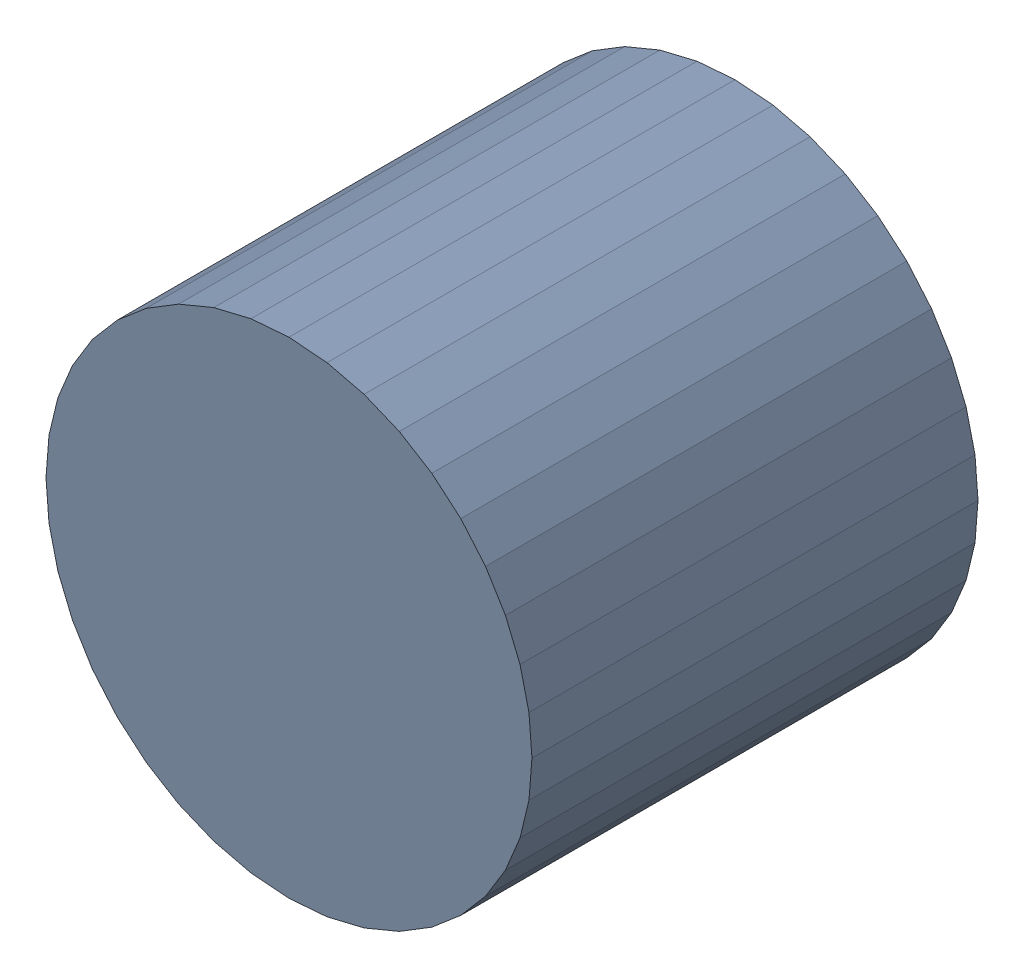
SolidWorks assembly CinMBypKanaloa_v2.0.0_Power, configuration Default. Lengths in mm.
Overall size (6.32 6.32 5.8).
2 component instances, 1 part files, 0 mates.
Components (placement in the parent):
- 352892112-1: 352892112 [Default] at (34.025 68.3 0) size (6.32 6.32 5.8)
  - Extruded_11-1: Extruded_11 [Default] at origin size (6.32 6.32 5.8)
